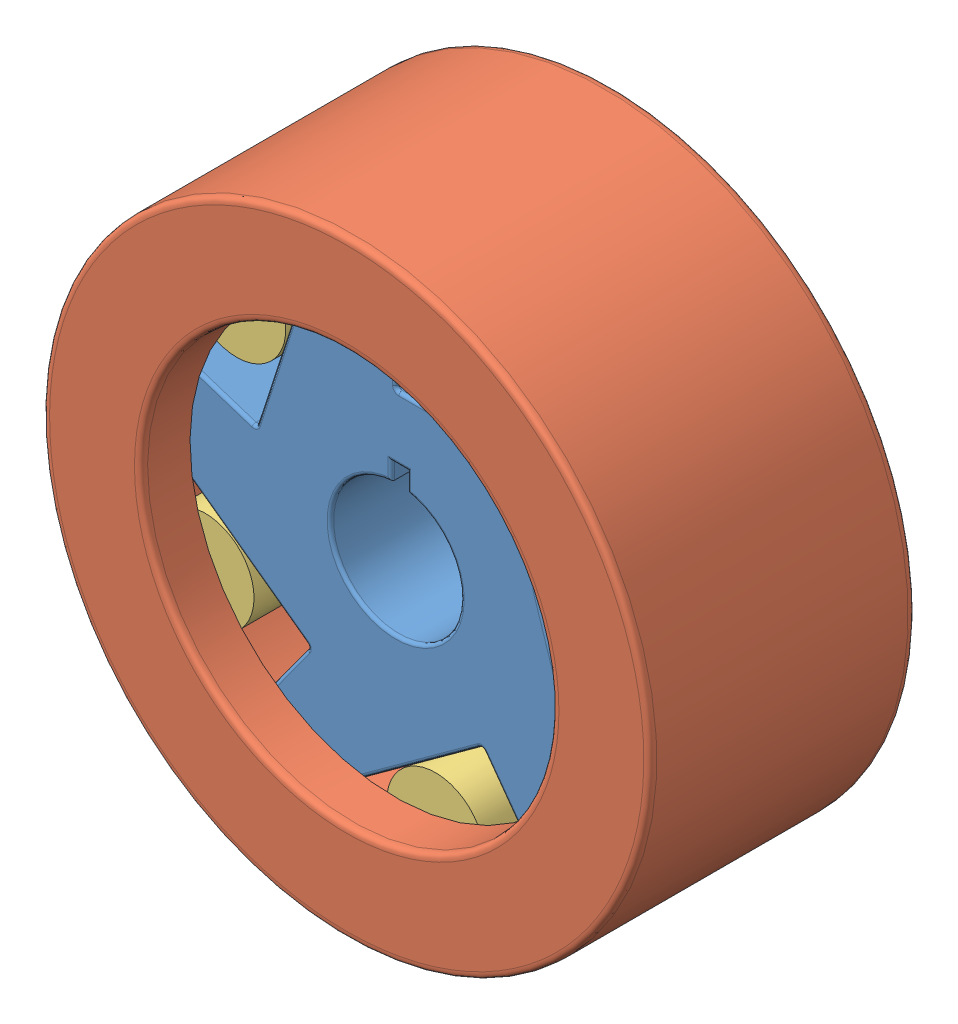
SolidWorks assembly One way bearing, configuration Default. Lengths in mm.
Overall size (201.4 201.4 81.1).
12 component instances, 4 part files, 40 mates.
Components (placement in the parent):
- inner rim-1: inner rim [Default] at (54.1979 78.8738 91.8361) size (151.02 151.08 50.06)
- outer rim-1: outer rim [Default] at (54.1979 78.8738 119.969) x (0 0 1) z (0.997957 0.063885 0) size (81.1 189.67 189.67)
- roller-1: roller [Default] at (81.1464 138.8738 91.8361) x (0 -1 0) z (0 0 1) size (30 30 50)
- roller-2: roller [Default] at (120.0196 70.4596 91.8361) x (-0.951057 -0.309017 0) z (0 0 1) size (30 30 50)
- roller-3: roller [Default] at (66.4384 13.6029 91.8361) x (-0.587785 0.809017 0) z (0 0 1) size (30 30 50)
- roller-4: roller [Default] at (-4.1842 47.1268 91.8361) x (0.587785 0.809017 0) z (0 0 1) size (30 30 50)
- roller-5: roller [Default] at (5.5466 123.3046 91.8361) x (0.951057 -0.309017 0) z (0 0 1) size (30 30 50)
- spring-2: spring [Default] at (-4.2547 95.9227 116.801) x (-0.899192 0.292165 -0.32572) z (0.309017 0.951057 0) size (11.99 11.99 24.48)
- spring-3: spring [Default] at (18.5812 28.971 116.8361) x (-0.387286 -0.533054 -0.752239) z (-0.809017 0.587785 0) size (11.99 11.99 24.48)
- spring-4: spring [Default] at (90.2896 30.1972 116.8361) x (0.307619 -0.423401 -0.852117) z (-0.809017 -0.587785 0) size (11.99 11.99 24.48)
- spring-5: spring [Default] at (110.8488 100.3511 116.8361) x (-0.483666 -0.157152 -0.861029) z (0.309017 -0.951057 0) size (11.99 11.99 24.48)
- spring-6: spring [Default] at (50.6209 140.1809 116.4224) x (0 -0.976164 -0.217032) z (1 0 0) size (11.99 11.99 24.48)
Mates (geometry in assembly coordinates):
- Coincident2: coincident aligned: plane of inner rim-1 through (54.1979 78.8738 141.8361) normal (0 0 1); plane of roller-1 through (81.1464 138.8738 141.8361) normal (0 0 1)
- Parallel2: parallel aligned: plane of inner rim-1 through (54.1979 78.8738 141.8361) normal (0 0 1); plane of roller-1 through (81.1464 138.8738 141.8361) normal (0 0 1)
- Parallel3: parallel aligned: plane of inner rim-1 through (54.1979 78.8738 141.8361) normal (1 0 0); plane of roller-1 through (81.1464 138.8738 91.8361) normal (1 0 0)
- Tangent7: tangent anti-aligned: plane of inner rim-1 through (54.1979 123.8738 141.8361) normal (0 1 0); cylinder of roller-1 through (81.1464 138.8738 141.8361) axis (0 0 -1) radius 15
- Coincident8: coincident aligned: plane of inner rim-1 through (54.1979 78.8738 141.8361) normal (0 0 1); plane of roller-2 through (120.0196 70.4596 141.8361) normal (0 0 1)
- Tangent8: tangent anti-aligned: plane of inner rim-1 through (96.9955 92.7795 141.8361) normal (0.951057 0.309017 0); cylinder of roller-2 through (120.0196 70.4596 141.8361) axis (0 0 -1) radius 15
- Parallel5: parallel aligned: plane of inner rim-1 through (54.1979 78.8738 141.8361) normal (0.309017 -0.951057 0); plane of roller-2 through (120.0196 70.4596 91.8361) normal (0.309017 -0.951057 0)
- Parallel9: parallel aligned: plane of inner rim-1 through (54.1979 78.8738 141.8361) normal (0 0 1); plane of roller-3 through (66.4384 13.6029 141.8361) normal (0 0 1)
- Tangent10: tangent anti-aligned: plane of inner rim-1 through (80.6483 42.468 141.8361) normal (0.587785 -0.809017 0); cylinder of roller-3 through (66.4384 13.6029 141.8361) axis (0 0 -1) radius 15
- Parallel10: parallel aligned: plane of inner rim-1 through (54.1979 78.8738 141.8361) normal (-0.809017 -0.587785 0); plane of roller-3 through (66.4384 13.6029 91.8361) normal (-0.809017 -0.587785 0)
- Coincident14: coincident aligned: plane of inner rim-1 through (54.1979 78.8738 141.8361) normal (0 0 1); plane of roller-3 through (66.4384 13.6029 141.8361) normal (0 0 1)
- Coincident15: coincident aligned: plane of inner rim-1 through (54.1979 78.8738 91.8361) normal (0 0 -1); plane of roller-4 through (-4.1842 47.1268 91.8361) normal (0 0 -1)
- Parallel13: parallel aligned: plane of inner rim-1 through (54.1979 78.8738 141.8361) normal (-0.809017 0.587785 0); plane of roller-4 through (-4.1842 47.1268 91.8361) normal (-0.809017 0.587785 0)
- Tangent11: tangent anti-aligned: plane of inner rim-1 through (27.7476 42.468 141.8361) normal (-0.587785 -0.809017 0); cylinder of roller-4 through (-4.1842 47.1268 141.8361) axis (0 0 -1) radius 15
- Parallel14: parallel aligned: plane of inner rim-1 through (54.1979 78.8738 91.8361) normal (0 0 -1); plane of roller-5 through (5.5466 123.3046 91.8361) normal (0 0 -1)
- Parallel15: parallel aligned: plane of inner rim-1 through (54.1979 78.8738 141.8361) normal (0.309017 0.951057 0); plane of roller-5 through (5.5466 123.3046 91.8361) normal (0.309017 0.951057 0)
- Coincident21: coincident aligned: plane of inner rim-1 through (54.1979 78.8738 91.8361) normal (0 0 -1); plane of roller-5 through (5.5466 123.3046 91.8361) normal (0 0 -1)
- Tangent12: tangent anti-aligned: plane of inner rim-1 through (11.4004 92.7795 141.8361) normal (-0.951057 0.309017 0); cylinder of roller-5 through (5.5466 123.3046 141.8361) axis (0 0 -1) radius 15
- Concentric8: concentric: circle of inner rim-1; circle of outer rim-1
- Parallel16: parallel aligned: plane of inner rim-1 through (54.1979 78.8738 141.8361) normal (0.309017 0.951057 0); plane of spring-2 through (-4.2547 95.9227 116.801) normal (0.309017 0.951057 0)
- Tangent14: tangent anti-aligned: cylinder of roller-5 through (5.5466 123.3046 141.8361) axis (0 0 -1) radius 15; face of spring-2
- Lock1: lock: unknown of inner rim-1; unknown of spring-2
- Lock2: lock: unknown of roller-5; unknown of spring-2
- Parallel17: parallel aligned: plane of inner rim-1 through (54.1979 78.8738 141.8361) normal (-0.809017 0.587785 0); plane of spring-3 through (18.5812 28.971 116.8361) normal (-0.809017 0.587785 0)
- Concentric9: concentric: cylinder of inner rim-1 through (26.2527 23.3974 116.8361) axis (-0.809017 0.587785 0) radius 5; point of spring-3
- Lock3: lock: unknown of inner rim-1; unknown of spring-3
- Lock4: lock: unknown of roller-4; unknown of spring-3
- Parallel20: parallel aligned: plane of inner rim-1 through (54.1979 78.8738 141.8361) normal (-0.809017 -0.587785 0); plane of spring-4 through (90.2896 30.1972 116.8361) normal (-0.809017 -0.587785 0)
- Concentric11: concentric: cylinder of inner rim-1 through (97.9045 35.7298 116.8361) axis (-0.809017 -0.587785 0) radius 5; point of spring-4
- Lock6: lock: unknown of inner rim-1; unknown of spring-4
- Lock7: lock: unknown of roller-3; unknown of spring-4
- Parallel21: parallel aligned: plane of inner rim-1 through (54.1979 78.8738 141.8361) normal (1 0 0); plane of spring-6 through (50.6209 140.1809 116.4224) normal (1 0 0)
- Concentric12: concentric: cylinder of inner rim-1 through (44.1979 140.1809 116.4224) axis (1 0 0) radius 5.0036; point of spring-6
- Lock8: lock: unknown of inner rim-1; unknown of spring-6
- Lock9: lock: unknown of roller-1; unknown of spring-6
- Parallel22: parallel aligned: plane of inner rim-1 through (54.1979 78.8738 141.8361) normal (0.309017 -0.951057 0); plane of spring-5 through (110.8488 100.3511 116.8361) normal (0.309017 -0.951057 0)
- Concentric13: concentric: cylinder of inner rim-1 through (108.661 107.0845 116.8361) axis (0.309017 -0.951057 0) radius 5; point of spring-5
- Lock10: lock: unknown of inner rim-1; unknown of spring-5
- Lock11: lock: unknown of roller-2; unknown of spring-5
- Coincident36: coincident anti-aligned: plane of inner rim-1 through (54.1979 78.8738 141.8361) normal (0 0 1); plane of outer rim-1 through (58.6699 9.0168 141.8361) normal (0 0 -1)
